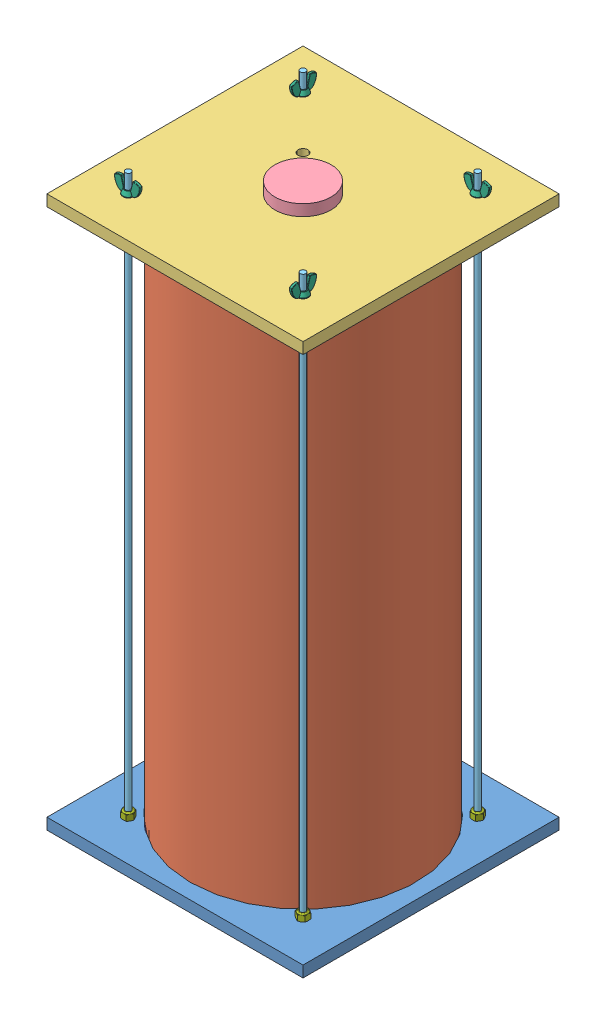
SolidWorks assembly A. Pressure tester assembly, configuration Default. Lengths in mm.
Overall size (293.75 661.26 293.75).
26 component instances, 8 part files, 21 mates.
Components (placement in the parent):
- Lid Botom-2: Lid Botom [Default] at (-226.9074 148.89 -140.2555) size (289.56 12.7 289.56)
- Optically Clear Cast Acrylic Tube-2: Optically Clear Cast Acrylic Tube [Default] at (-226.9074 460.3956 -140.2555) x (-0.171282 0 -0.985222) z (0.985222 0 -0.171282) size (254 609.6 254)
- Lid Top-2: Lid Top [Default] at (-226.9074 759.3536 -140.2555) x (0 0 1) z (-1 0 0) size (289.56 12.7 289.56)
- Metric Stainless Steel-Case Liquid-Filled Gauge with Bar&PSI-3: Metric Stainless Steel-Case Liquid-Filled Gauge with Bar&PSI [Default] at (-226.9074 772.0536 -140.2555) x (0.956797 0 -0.290757) z (0.290757 0 0.956797) size (63.5 25.4 63.5)
- Threaded Rod 1.4-20-8: Threaded Rod 1.4-20 [Default] at (-128.1245 464.0786 -41.4726) x (-0.994842 0 -0.101433) z (0.101433 0 -0.994842) size (6.35 660.4 6.35)
- Threaded Rod 1.4-20-9: Threaded Rod 1.4-20 [Default] at (-128.1245 464.0786 -239.0383) x (-0.101433 0 0.994842) z (-0.994842 0 -0.101433) size (6.35 660.4 6.35)
- Threaded Rod 1.4-20-10: Threaded Rod 1.4-20 [Default] at (-325.6902 464.0786 -239.0383) x (0.994842 0 0.101433) z (-0.101433 0 0.994842) size (6.35 660.4 6.35)
- Threaded Rod 1.4-20-11: Threaded Rod 1.4-20 [Default] at (-325.6902 464.0786 -41.4726) x (0.101433 0 -0.994842) z (0.994842 0 0.101433) size (6.35 660.4 6.35)
- #1.4-20 -7: #1.4-20  [93575A029] at (-128.1245 148.89 -41.4726) x (0.837169 0 0.546944) z (0 1 0) size (28.57 12.25 16.35)
- #1.4-20 - 91831A029-12: #1.4-20 - 91831A029 [91831A029] at (-128.1245 161.59 -41.4726) size (11.11 7.94 12.83)
- #1.4-20 -8: #1.4-20  [93575A029] at (-128.1245 148.89 -239.0383) x (0.546944 0 -0.837169) z (0 1 0) size (28.57 12.25 16.35)
- #1.4-20 -9: #1.4-20  [93575A029] at (-325.6902 148.89 -239.0383) x (-0.837169 0 -0.546944) z (0 1 0) size (28.57 12.25 16.35)
- #1.4-20 -10: #1.4-20  [93575A029] at (-325.6902 148.89 -41.4726) x (-0.546944 0 0.837169) z (0 1 0) size (28.57 12.25 16.35)
- #1.4-20 -13: #1.4-20  [93575A029] at (-325.6902 772.0536 -41.4726) x (0.999946 0 -0.010363) z (0 -1 0) size (28.57 12.25 16.35)
- #1.4-20 -14: #1.4-20  [93575A029] at (-128.1245 772.0536 -41.4726) x (-0.010363 0 -0.999946) z (0 -1 0) size (28.57 12.25 16.35)
- #1.4-20 -15: #1.4-20  [93575A029] at (-128.1245 772.0536 -239.0383) x (-0.999946 0 0.010363) z (0 -1 0) size (28.57 12.25 16.35)
- #1.4-20 -16: #1.4-20  [93575A029] at (-325.6902 772.0536 -239.0383) x (0.010363 0 0.999946) z (0 -1 0) size (28.57 12.25 16.35)
- 1.8 - 9_3.4 - 9452K372-1: 1.8 - 9_3.4 - 9452K372 [9452K372] at (-226.9074 153.8303 -140.2555) x (1 0 0) z (0 -1 0) size (254.3 254.3 3.53)
- 1.8 - 9_3.4 - 9452K372-2: 1.8 - 9_3.4 - 9452K372 [9452K372] at (-226.9074 767.1133 -140.2555) x (1 0 0) z (0 -1 0) size (254.3 254.3 3.53)
- #1.4-20 - 91831A029-24: #1.4-20 - 91831A029 [91831A029] at (-325.6902 759.3536 -239.0383) x (-0.837169 0 -0.546944) z (-0.546944 0 0.837169) size (11.11 7.94 12.83)
- #1.4-20 - 91831A029-28: #1.4-20 - 91831A029 [91831A029] at (-128.1245 759.3536 -239.0383) x (0.546944 0 -0.837169) z (-0.837169 0 -0.546944) size (11.11 7.94 12.83)
- #1.4-20 - 91831A029-29: #1.4-20 - 91831A029 [91831A029] at (-128.1245 759.3536 -41.4726) x (0.837169 0 0.546944) z (0.546944 0 -0.837169) size (11.11 7.94 12.83)
- #1.4-20 - 91831A029-30: #1.4-20 - 91831A029 [91831A029] at (-325.6902 759.3536 -41.4726) x (-0.546944 0 0.837169) z (0.837169 0 0.546944) size (11.11 7.94 12.83)
- #1.4-20 - 91831A029-31: #1.4-20 - 91831A029 [91831A029] at (-325.6902 161.59 -41.4726) x (0 0 1) z (-1 0 0) size (11.11 7.94 12.83)
- #1.4-20 - 91831A029-32: #1.4-20 - 91831A029 [91831A029] at (-325.6902 161.59 -239.0383) x (-1 0 0) z (0 0 -1) size (11.11 7.94 12.83)
- #1.4-20 - 91831A029-33: #1.4-20 - 91831A029 [91831A029] at (-128.1245 161.59 -239.0383) x (0 0 -1) z (1 0 0) size (11.11 7.94 12.83)
Mates (geometry in assembly coordinates):
- Distance3: distance = 3.5306 mm anti-aligned: plane of Lid Botom-2 through (-226.9074 152.065 -140.2555) normal (0 1 0); plane of Optically Clear Cast Acrylic Tube-2 through (-226.9074 155.5956 -140.2555) normal (0 -1 0)
- Concentric3: concentric aligned: cylinder of Lid Top-2 through (-226.9074 772.0536 -140.2555) axis (0 1 0) radius 5.5626; cylinder of Metric Stainless Steel-Case Liquid-Filled Gauge with Bar&PSI-3 through (-226.9074 759.3536 -140.2555) axis (0 1 0) radius 5.588
- Coincident5: coincident anti-aligned: plane of Lid Top-2 through (-226.9074 772.0536 -140.2555) normal (0 1 0); plane of Metric Stainless Steel-Case Liquid-Filled Gauge with Bar&PSI-3 through (-226.9074 772.0536 -140.2555) normal (0 -1 0)
- Concentric5: concentric aligned: cylinder of Lid Botom-2 through (-226.9074 152.065 -140.2555) axis (0 1 0) radius 127.635; cylinder of Optically Clear Cast Acrylic Tube-2 through (-226.9074 155.5956 -140.2555) axis (0 1 0) radius 127
- Concentric6: concentric anti-aligned: cylinder of Optically Clear Cast Acrylic Tube-2 through (-226.9074 155.5956 -140.2555) axis (0 1 0) radius 127; cylinder of Lid Top-2 through (-226.9074 768.8786 -140.2555) axis (0 -1 0) radius 123.19
- Distance5: distance = 3.683 mm anti-aligned: plane of Optically Clear Cast Acrylic Tube-2 through (-226.9074 765.1956 -140.2555) normal (0 1 0); plane of Lid Top-2 through (-226.9074 768.8786 -140.2555) normal (0 -1 0)
- Coincident7: coincident aligned: plane of Lid Botom-2 through (-82.1274 161.59 4.5245) normal (1 0 0); plane of Lid Top-2 through (-82.1274 772.0536 -285.0355) normal (1 0 0)
- Concentric7: concentric aligned: cylinder of Lid Top-2 through (-128.1245 772.0536 -41.4726) axis (0 1 0) radius 3.3782; cylinder of Threaded Rod 1.4-20-8 through (-128.1245 133.8786 -41.4726) axis (0 1 0) radius 3.175
- Distance1: distance = 22.225 mm aligned: plane of Lid Top-2 through (-226.9074 772.0536 -140.2555) normal (0 1 0); plane of Threaded Rod 1.4-20-8 through (-128.1245 794.2786 -41.4726) normal (0 1 0)
- Concentric8: concentric anti-aligned: cylinder of Threaded Rod 1.4-20-8 through (-128.1245 133.8786 -41.4726) axis (0 1 0) radius 3.175; cylinder of #1.4-20 - 91831A029-12 through (-128.1245 168.2808 -41.4726) axis (0 -1 0) radius 2.6099
- Coincident9: coincident anti-aligned: plane of Lid Botom-2 through (-226.9074 161.59 -140.2555) normal (0 1 0); plane of #1.4-20 - 91831A029-12 through (-133.6808 161.59 -51.0964) normal (0 -1 0)
- Concentric9: concentric aligned: cylinder of Threaded Rod 1.4-20-8 through (-128.1245 133.8786 -41.4726) axis (0 1 0) radius 3.175; circle of #1.4-20 -7
- Coincident10: coincident anti-aligned: plane of Lid Botom-2 through (-226.9074 148.89 -140.2555) normal (0 -1 0); plane of #1.4-20 -7 through (-128.1245 148.89 -41.4726) normal (0 1 0)
- Coincident15: coincident anti-aligned: plane of Lid Top-2 through (-226.9074 772.0536 -140.2555) normal (0 1 0); plane of #1.4-20 -13 through (-325.6902 772.0536 -41.4726) normal (0 -1 0)
- Concentric10: concentric anti-aligned: cylinder of Threaded Rod 1.4-20-11 through (-325.6902 133.8786 -41.4726) axis (0 1 0) radius 3.175; circle of #1.4-20 -13
- Coincident16: coincident anti-aligned: axis of Lid Botom-2 through (-226.9074 152.065 -140.2555) axis (0 1 0); axis of 1.8 - 9_3.4 - 9452K372-1 through (-226.9074 225.7621 -140.2555) axis (0 -1 0)
- Tangent7: tangent: plane of Lid Botom-2 through (-226.9074 152.065 -140.2555) normal (0 1 0); torus of 1.8 - 9_3.4 - 9452K372-1
- Coincident20: coincident anti-aligned: axis of Lid Top-2 through (-226.9074 759.3536 -140.2555) axis (0 1 0); axis of 1.8 - 9_3.4 - 9452K372-2 through (-226.9074 839.0451 -140.2555) axis (0 -1 0)
- Tangent9: tangent: plane of Lid Top-2 through (-226.9074 768.8786 -140.2555) normal (0 -1 0); torus of 1.8 - 9_3.4 - 9452K372-2
- Coincident21: coincident anti-aligned: plane of Lid Top-2 through (-226.9074 759.3536 -140.2555) normal (0 -1 0); plane of #1.4-20 - 91831A029-24 through (-315.775 759.3536 -244.056) normal (0 1 0)
- Coincident22: coincident aligned: cylinder of Threaded Rod 1.4-20-10 through (-325.6902 133.8786 -239.0383) axis (0 1 0) radius 3.175; circle of #1.4-20 - 91831A029-24
